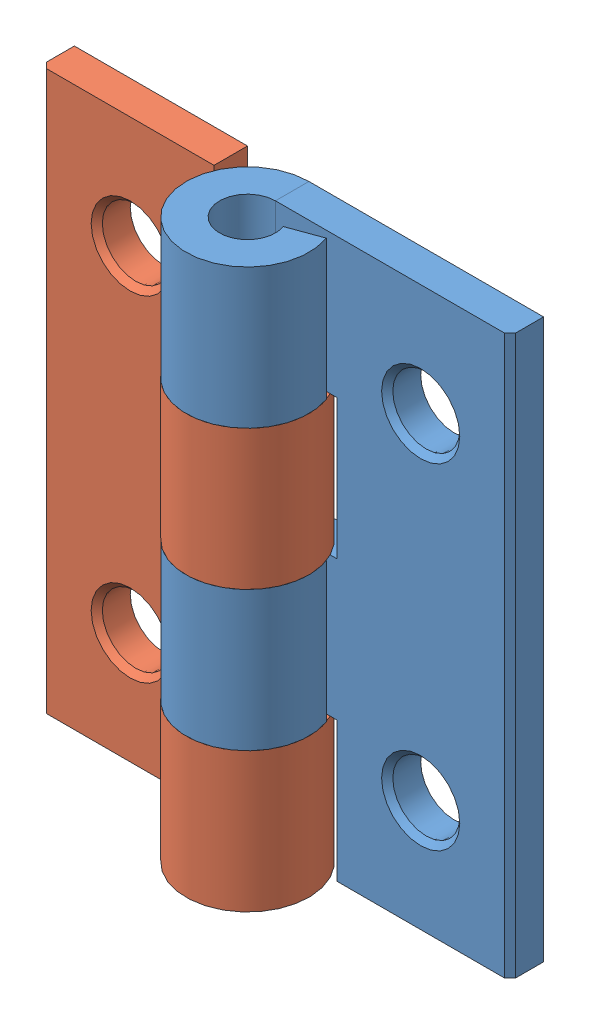
SolidWorks assembly hingeAssembly, configuration Default. Lengths in mm.
Overall size (42 50 11).
2 component instances, 2 part files, 6 mates.
Components (placement in the parent):
- Hinge A-1: Hinge A [Default] at origin size (26.5 50 11)
- Hinge B-1: Hinge B [Default] at (-21 0 0) size (26.5 50 11)
Mates (geometry in assembly coordinates):
- Coincident1: coincident aligned: plane of Hinge A-1 through (0 0 0) normal (0 1 0)
- Coincident2: coincident aligned: plane of Hinge A-1 through (0 0 0) normal (0 0 1)
- Coincident3: coincident aligned: plane of Hinge A-1 through (0 0 0) normal (1 0 0)
- Concentric1: concentric: cylinder of Hinge A-1 through (-10.5 12.5 5.5) axis (0 -1 0) radius 2.5; cylinder of Hinge B-1 through (-10.5 12.5 5.5) axis (0 1 0) radius 2.5
- Coincident4: coincident: plane of Hinge A-1 through (-10.5 12.5 5.5) normal (0 -1 0); plane of Hinge B-1 through (-10.5 12.5 5.5) normal (0 1 0)
- Coincident5: coincident aligned: plane of Hinge A-1 through (0 0 0) normal (0 0 -1); plane of Hinge B-1 through (-21 0 0) normal (0 0 -1)
